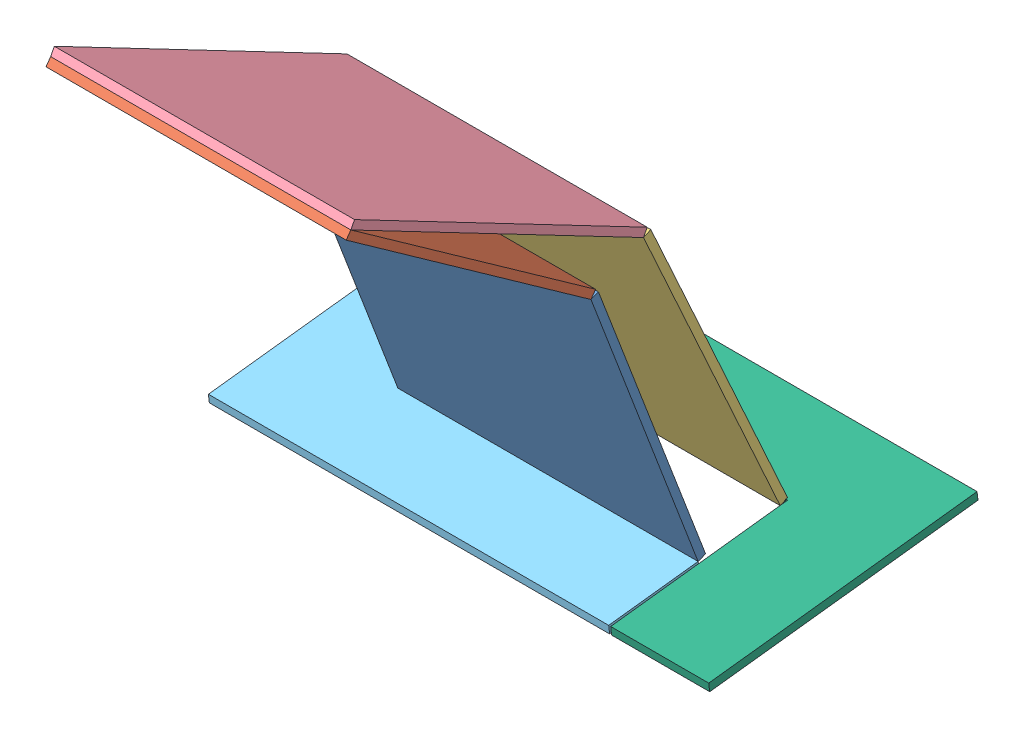
SolidWorks assembly folded, configuration Default. Lengths in mm.
Overall size (250 243.03 265.68).
6 component instances, 6 part files, 12 mates.
Components (placement in the parent):
- A-1: A [Default] at (-59.848 42.8158 160.603) x (1 0 0) z (0 -0.934153 -0.356873) size (150 4 150)
- B-1: B [Default] at (-59.848 115.7469 74.04) x (1 0 0) z (0 -0.578957 -0.815358) size (150 4 150)
- C-1: C [Default] at (-59.848 698.3652 426.2588) x (1 0 0) z (0 0.910223 0.414119) size (150 4 165)
- D-1: D [Default] at (-59.848 468.462 665.2762) x (1 0 0) z (0 0.463135 0.886288) size (150 4 165)
- EA-1: EA [Default] at (-59.848 68.7727 227.8859) x (1 0 0) z (0 -0.11734 0.993092) size (200 4 135)
- EC-1: EC [Default] at (-59.848 0.1289 808.8446) x (1 0 0) z (0 -0.11734 0.993092) size (200 4 135)
Mates (geometry in assembly coordinates):
- Coincident3: coincident aligned: line of C-1 through (140.152 235.8082 211.417) axis (-1 0 0); line of D-1 through (140.152 235.8082 211.417) axis (-1 0 0)
- Coincident4: coincident aligned: line of C-1 through (-9.848 87.278 139.4464) axis (1 0 0); line of EC-1 through (-9.848 87.278 139.4464) axis (1 0 0)
- Coincident5: coincident aligned: plane of C-1 through (-9.848 700.0217 422.6179) normal (-1 0 0); plane of EC-1 through (-9.848 4.1012 809.314) normal (-1 0 0)
- Coincident6: coincident aligned: plane of D-1 through (-9.848 472.0072 663.4237) normal (-1 0 0); plane of EC-1 through (-9.848 4.1012 809.314) normal (-1 0 0)
- Coincident7: coincident aligned: line of A-1 through (140.152 81.9977 184.1355) axis (-1 0 0); line of EA-1 through (140.152 81.9977 184.1355) axis (-1 0 0)
- Coincident9: coincident aligned: plane of A-1 through (140.152 41.3883 164.3396) normal (1 0 0); plane of EA-1 through (140.152 72.745 228.3553) normal (1 0 0)
- Coincident10: coincident aligned: plane of B-1 through (140.152 112.4855 76.3558) normal (1 0 0); plane of EA-1 through (140.152 72.745 228.3553) normal (1 0 0)
- Coincident12: coincident aligned: line of A-1 through (140.152 222.1206 237.6665) axis (-1 0 0); line of B-1 through (140.152 222.1206 237.6665) axis (-1 0 0)
- Coincident13: coincident aligned: line of B-1 through (140.152 312.2255 357.6544) axis (-1 0 0); line of D-1 through (140.152 312.2255 357.6544) axis (-1 0 0)
- Coincident14: coincident aligned: plane of B-1 through (-9.848 112.4855 76.3558) normal (-1 0 0); plane of D-1 through (-9.848 472.0072 663.4237) normal (-1 0 0)
- Coincident16: coincident aligned: plane of EA-1 through (-59.848 76.7174 228.8246) normal (0 0.993092 0.11734); plane of EC-1 through (-59.848 8.0736 809.7834) normal (0 0.993092 0.11734)
- Coincident17: coincident aligned: plane of EA-1 through (-59.848 72.745 228.3553) normal (0 -0.11734 0.993092); plane of EC-1 through (-59.848 72.745 228.3553) normal (0 -0.11734 0.993092)
